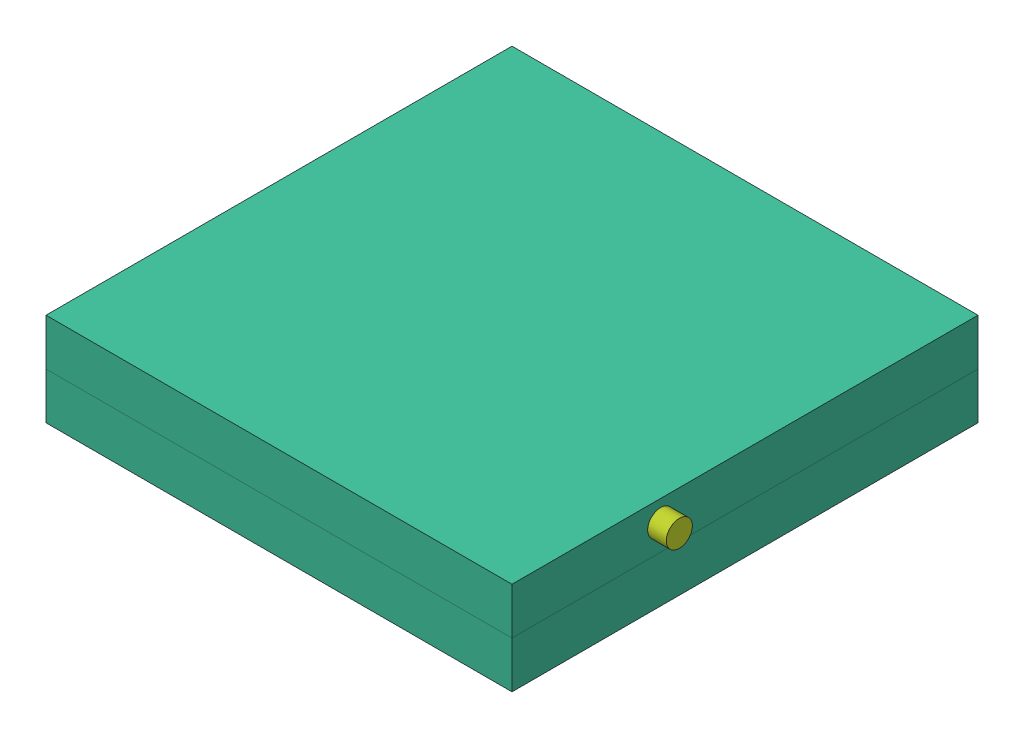
SolidWorks assembly Clock, configuration Default. Lengths in mm.
Overall size (52 10 50).
15 component instances, 8 part files, 50 mates.
Components (placement in the parent):
- Battery-1: Battery [Default] at (11.5775 17.3072 29.3561) size (25 4 35.8)
- Vibro-1: Vibro [Default] at (-4.1725 21.9572 32.7561) x (0 0 -1) z (-0.968138 0.250416 0) size (15.3 6.5 6.5)
- Display-1: Display [Default] at (11.7275 23.4572 28.3061) x (0 0 -1) z (1 0 0) size (26.7 1.35 19.3)
- Conn-2: Conn [Default] at (-10.5225 18.8572 36.2561) size (3 3.3 10)
- Button-7: Button [Default] at (25.8227 21.9072 39.0061) x (0 0 -1) z (1 0 0) size (4.5 1.8 3.55)
- Button-8: Button [Default] at (25.4275 21.9072 29.5061) x (0 0 -1) z (1 0 0) size (4.5 1.8 3.55)
- Button-9: Button [Default] at (25.4275 21.9072 19.7061) x (0 0 -1) z (1 0 0) size (4.5 1.8 3.55)
- Button-10: Button [Default] at (-2.2725 21.9072 39.0061) x (0 0 1) z (-1 0 0) size (4.5 1.8 3.55)
- bottom case-1: bottom case [Default] at (12.0775 16.2072 29.7561) x (0 0 1) z (-1 0 0) size (50 5 50)
- bottom case-2: bottom case [Default] at (12.0775 26.2072 29.7561) x (0 0 1) z (1 0 0) size (50 5 50)
- ButtonHandle-2: ButtonHandle [Default] at (29.0775 23.9572 38.8061) size (10.5 3.5 3.5)
- Nut-1: Nut [Default] at (26.5775 23.2072 44.7561) size (5 2 5)
- Nut-2: Nut [Default] at (26.5775 23.2072 13.9561) size (5 2 5)
- Nut-3: Nut [Default] at (-3.4225 23.2072 44.7561) size (5 2 5)
- Nut-4: Nut [Default] at (-3.4225 23.2072 13.9561) x (-0.999994 0 -0.003394) z (0.003394 0 -0.999994) size (5 2 5)
Mates (geometry in assembly coordinates):
- Parallel3: parallel anti-aligned: plane of Battery-1 through (11.5775 21.3072 29.3561) normal (0 1 0); plane of Display-1 through (11.7275 23.4572 28.3061) normal (0 -1 0)
- Parallel4: parallel aligned: line of Battery-1 through (0.5775 21.3072 11.4561) axis (0 0 1); line of Display-1 through (2.0775 24.8072 14.9561) axis (0 0 1)
- Distance2: distance = 3 mm aligned: plane of Display-1 through (2.0775 24.8072 14.9561) normal (-1 0 0); plane of Battery-1 through (-0.9225 21.3072 11.4561) normal (-1 0 0)
- Parallel10: parallel anti-aligned: plane of Battery-1 through (24.0775 21.3072 11.4561) normal (1 0 0); plane of Button-9 through (24.2775 23.7072 17.4561) normal (-1 0 0)
- Parallel11: parallel anti-aligned: plane of Battery-1 through (24.0775 21.3072 11.4561) normal (1 0 0); plane of Button-8 through (24.2775 23.7072 27.2561) normal (-1 0 0)
- Parallel12: parallel anti-aligned: plane of Battery-1 through (24.0775 21.3072 11.4561) normal (1 0 0); plane of Button-7 through (24.6727 23.7072 36.7561) normal (-1 0 0)
- Parallel13: parallel anti-aligned: plane of Battery-1 through (-0.9225 21.3072 11.4561) normal (-1 0 0); plane of Conn-2 through (-7.5225 18.8572 36.2561) normal (1 0 0)
- Parallel14: parallel anti-aligned: plane of Battery-1 through (-0.9225 21.3072 11.4561) normal (-1 0 0); plane of Button-10 through (-1.1225 23.7072 41.2561) normal (1 0 0)
- Distance9: distance = 3.5 mm aligned: plane of Display-1 through (21.3775 24.8072 14.9561) normal (0 0 -1); plane of Battery-1 through (-0.9225 21.3072 11.4561) normal (0 0 -1)
- Coincident28: coincident aligned: line of Button-8 through (24.2775 23.7072 27.2561) axis (0 0 1); line of Button-9 through (24.2775 23.7072 17.4561) axis (0 0 1)
- Distance12: distance = 0.2 mm anti-aligned: plane of Button-9 through (24.2775 23.7072 17.4561) normal (-1 0 0); plane of Battery-1 through (24.0775 21.3072 11.4561) normal (1 0 0)
- Distance13: distance = 0.2 mm anti-aligned: plane of Button-10 through (-1.1225 23.7072 41.2561) normal (1 0 0); plane of Battery-1 through (-0.9225 21.3072 11.4561) normal (-1 0 0)
- Distance14: distance = 6 mm aligned: plane of Button-9 through (24.2775 23.7072 17.4561) normal (0 0 -1); plane of Battery-1 through (-0.9225 21.3072 11.4561) normal (0 0 -1)
- Distance15: distance = 6 mm aligned: plane of Button-7 through (24.6727 23.7072 41.2561) normal (0 0 1); plane of Battery-1 through (-0.9225 21.3072 47.2561) normal (0 0 1)
- Distance16: distance = 20 mm anti-aligned: plane of Button-8 through (24.2775 23.7072 27.2561) normal (0 0 -1); plane of Battery-1 through (-0.9225 21.3072 47.2561) normal (0 0 1)
- Tangent5: tangent anti-aligned: plane of Battery-1 through (-0.9225 21.3072 11.4561) normal (-1 0 0); cylinder of Vibro-1 through (-4.1725 21.9572 17.4561) axis (0 0 1) radius 3.25
- Distance20: distance = 0.1 mm anti-aligned: plane of bottom case-1 through (12.0775 17.2072 29.7561) normal (0 1 0); plane of Battery-1 through (11.5775 17.3072 29.3561) normal (0 -1 0)
- Parallel15: parallel anti-aligned: plane of Battery-1 through (-0.9225 21.3072 47.2561) normal (0 0 1); plane of bottom case-1 through (-9.9225 21.2072 52.2561) normal (0 0 -1)
- Distance21: distance = 5 mm anti-aligned: plane of bottom case-1 through (-9.9225 21.2072 52.2561) normal (0 0 -1); plane of Battery-1 through (-0.9225 21.3072 47.2561) normal (0 0 1)
- Distance22: distance = 9 mm anti-aligned: plane of bottom case-1 through (-9.9225 21.2072 52.2561) normal (1 0 0); plane of Battery-1 through (-0.9225 21.3072 11.4561) normal (-1 0 0)
- Parallel18: parallel aligned: plane of Battery-1 through (11.5775 21.3072 29.3561) normal (0 1 0); plane of Button-7 through (25.8227 23.7072 39.0061) normal (0 1 0)
- Coincident42: coincident anti-aligned: plane of Conn-2 through (-7.5225 17.2072 31.2561) normal (0 -1 0); plane of bottom case-1 through (12.0775 17.2072 29.7561) normal (0 1 0)
- Coincident45: coincident anti-aligned: plane of bottom case-1 through (12.0775 21.2072 29.7561) normal (0 1 0); plane of bottom case-2 through (12.0775 21.2072 29.7561) normal (0 -1 0)
- Distance23: distance = 1.4 mm aligned: plane of Display-1 through (11.7275 24.8072 28.3061) normal (0 1 0); plane of bottom case-2 through (12.0775 26.2072 29.7561) normal (0 1 0)
- Coincident55: coincident aligned: plane of bottom case-1 through (-12.9225 17.2072 54.7561) normal (0 0 1); plane of bottom case-2 through (37.0775 25.2072 54.7561) normal (0 0 1)
- Coincident56: coincident aligned: plane of bottom case-1 through (37.0775 17.2072 54.7561) normal (1 0 0); plane of bottom case-2 through (37.0775 25.2072 54.7561) normal (1 0 0)
- Distance26: distance = 0.6 mm anti-aligned: plane of Button-7 through (25.8227 21.9072 39.0061) normal (0 -1 0); plane of Battery-1 through (11.5775 21.3072 29.3561) normal (0 1 0)
- Parallel24: parallel aligned: plane of bottom case-2 through (37.0775 25.2072 54.7561) normal (1 0 0); plane of ButtonHandle-2 through (39.0775 23.9572 38.8061) normal (1 0 0)
- Distance33: distance = 0.5 mm aligned: plane of bottom case-2 through (12.0775 26.2072 29.7561) normal (0 1 0); cylinder of ButtonHandle-2 through (34.0775 23.9572 38.8061) axis (-1 0 0) radius 1.75
- Distance34: distance = 14.2 mm aligned: plane of bottom case-2 through (37.0775 25.2072 54.7561) normal (0 0 1); cylinder of ButtonHandle-2 through (34.0775 23.9572 38.8061) axis (-1 0 0) radius 1.75
- Distance35: distance = 2 mm aligned: plane of ButtonHandle-2 through (39.0775 23.9572 38.8061) normal (1 0 0); plane of bottom case-2 through (37.0775 25.2072 54.7561) normal (1 0 0)
- Coincident57: coincident aligned: plane of Nut-3 through (-3.4225 25.2072 44.7561) normal (0 1 0); circle of Nut-4
- Coincident58: coincident aligned: plane of Nut-3 through (-3.4225 25.2072 44.7561) normal (0 1 0); plane of Nut-2 through (26.5775 25.2072 13.9561) normal (0 1 0)
- Coincident59: coincident aligned: plane of Nut-3 through (-3.4225 25.2072 44.7561) normal (0 1 0); plane of Nut-1 through (26.5775 25.2072 44.7561) normal (0 1 0)
- Distance37: distance = 1 mm aligned: plane of Nut-3 through (-3.4225 25.2072 44.7561) normal (0 1 0); plane of bottom case-2 through (12.0775 26.2072 29.7561) normal (0 1 0)
- Tangent8: tangent aligned: plane of Battery-1 through (-0.9225 21.3072 11.4561) normal (0 0 -1); cylinder of Nut-2 through (26.5775 25.2072 13.9561) axis (0 -1 0) radius 2.5
- Tangent9: tangent aligned: plane of Battery-1 through (-0.9225 21.3072 11.4561) normal (0 0 -1); cylinder of Nut-4 through (-3.4225 25.2072 13.9561) axis (0 -1 0) radius 2.5
- Tangent10: tangent aligned: plane of Battery-1 through (-0.9225 21.3072 47.2561) normal (0 0 1); cylinder of Nut-1 through (26.5775 25.2072 44.7561) axis (0 -1 0) radius 2.5
- Tangent11: tangent aligned: plane of Battery-1 through (-0.9225 21.3072 47.2561) normal (0 0 1); cylinder of Nut-3 through (-3.4225 25.2072 44.7561) axis (0 -1 0) radius 2.5
- Distance38: distance = 1 mm anti-aligned: plane of Button-10 through (-1.1225 23.7072 41.2561) normal (0 0 1); cylinder of Nut-3 through (-3.4225 25.2072 44.7561) axis (0 -1 0) radius 2.5
- Distance39: distance = 1 mm anti-aligned: cylinder of Nut-4 through (-3.4225 25.2072 13.9561) axis (0 -1 0) radius 2.5; plane of Vibro-1 through (-4.1725 21.9572 17.4561) normal (0 0 -1)
- Tangent15: tangent aligned: cylinder of Vibro-1 through (-4.1725 21.9572 17.4561) axis (0 0 1) radius 3.25; plane of Nut-4 through (-3.4225 25.2072 13.9561) normal (0 1 0)
- Distance40: distance = 1 mm anti-aligned: plane of Conn-2 through (-7.5225 19.6072 41.2561) normal (0 0 1); cylinder of Nut-3 through (-3.4225 25.2072 44.7561) axis (0 -1 0) radius 2.5
- Tangent17: tangent anti-aligned: plane of Battery-1 through (-0.9225 21.3072 11.4561) normal (-1 0 0); cylinder of Nut-4 through (-3.4225 25.2072 13.9561) axis (0 -1 0) radius 2.5
- Tangent18: tangent anti-aligned: plane of Battery-1 through (-0.9225 21.3072 11.4561) normal (-1 0 0); cylinder of Nut-3 through (-3.4225 25.2072 44.7561) axis (0 -1 0) radius 2.5
- Tangent20: tangent anti-aligned: plane of Battery-1 through (24.0775 21.3072 11.4561) normal (1 0 0); cylinder of Nut-2 through (26.5775 25.2072 13.9561) axis (0 -1 0) radius 2.5
- Tangent21: tangent anti-aligned: plane of Battery-1 through (24.0775 21.3072 11.4561) normal (1 0 0); cylinder of Nut-1 through (26.5775 25.2072 44.7561) axis (0 -1 0) radius 2.5
- Distance41: distance = 0.6 mm anti-aligned: plane of Button-10 through (-2.2725 21.9072 39.0061) normal (0 -1 0); plane of Battery-1 through (11.5775 21.3072 29.3561) normal (0 1 0)
- Distance42: distance = 0.6 mm anti-aligned: plane of Button-9 through (25.4275 21.9072 19.7061) normal (0 -1 0); plane of Battery-1 through (11.5775 21.3072 29.3561) normal (0 1 0)
- Distance43: distance = 0.1 mm anti-aligned: plane of Conn-2 through (-7.5225 18.8572 36.2561) normal (1 0 0); cylinder of Vibro-1 through (-4.1725 21.9572 17.4561) axis (0 0 1) radius 3.25
